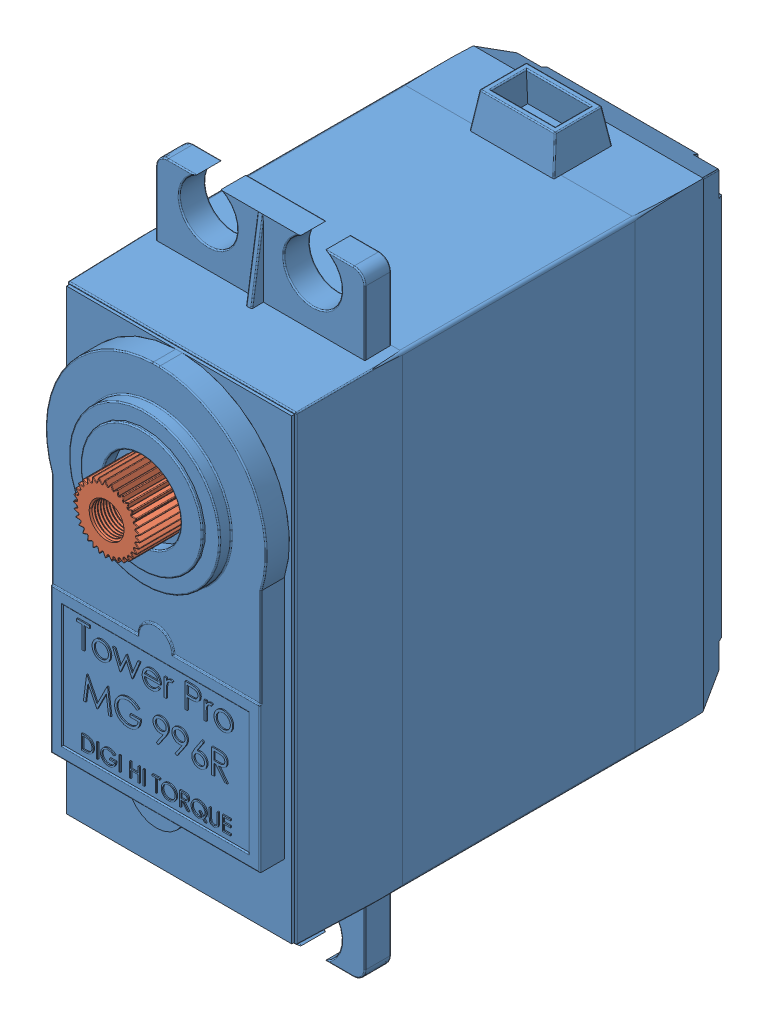
SolidWorks assembly main_assembly, configuration Default. Lengths in mm.
Overall size (20 53 44.5).
2 component instances, 2 part files, 2 mates.
Components (placement in the parent):
- main_body-1: main_body [Default] at (15.1003 34.2066 38.7045)
- gear-1: gear [Default] at (15.0988 44.3995 70.2045) x (0.991102 -0.133104 0) z (0 0 1)
Mates (geometry in assembly coordinates):
- Concentric1: concentric: circle of main_body-1; circle of gear-1
- Coincident2: coincident: plane of main_body-1 through (15.0988 44.3995 70.2045) normal (0 0 1); plane of gear-1 through (15.0988 44.3995 70.2045) normal (0 0 -1)
